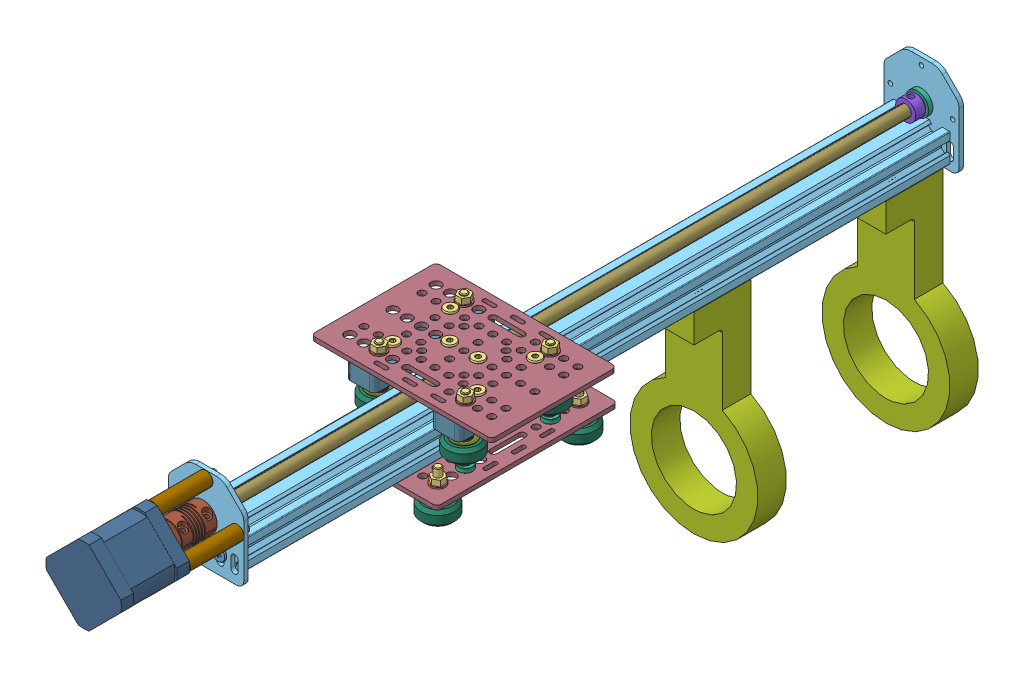
SolidWorks assembly Dispenser Actuator, configuration Default. Lengths in mm.
Overall size (127 213.42 594.1).
122 component instances, 26 part files, 152 mates.
Components (placement in the parent):
- Self Tapping Screw-1: Self Tapping Screw [Default] at (-10 5.04 578.9927) x (-0.969489 0.245134 0) z (0.245134 0.969489 0) size (9.6 20.4 9.6)
- Self Tapping Screw-3: Self Tapping Screw [Default] at (10 5.04 578.9927) x (-0.969489 0.245134 0) z (0.245134 0.969489 0) size (9.6 20.4 9.6)
- Socket Head Cap Screw M3-1: Socket Head Cap Screw M3 [M3 x 45] at (21.9203 23.47 620.9927) x (0 0 1) z (-1 0 0) size (48.09 5.5 5.5)
- Socket Head Cap Screw M3-2: Socket Head Cap Screw M3 [M3 x 45] at (0 45.3903 620.9927) x (0 0 1) z (-1 0 0) size (48.09 5.5 5.5)
- Socket Head Cap Screw M3-3: Socket Head Cap Screw M3 [M3 x 45] at (-21.9203 23.47 620.9927) x (0 0 1) z (-1 0 0) size (48.09 5.5 5.5)
- Self Tapping Screw-4: Self Tapping Screw [Default] at (10 5.04 72.9927) x (1 0 0) z (0 1 0) size (9.6 20.4 9.6)
- Self Tapping Screw-6: Self Tapping Screw [Default] at (-10 5.04 72.9927) x (1 0 0) z (0 1 0) size (9.6 20.4 9.6)
- Low Profile Screw M5-7: Low Profile Screw M5 [M5 x 15] at (-29.85 17.47 377.4168) x (0 -1 0) z (0 0 1) size (16.62 9 9)
- Low Profile Screw M5-8: Low Profile Screw M5 [M5 x 15] at (-29.85 17.47 418.0568) x (0 -1 0) z (0 0 1) size (16.62 9 9)
- Low Profile Screw M5-9: Low Profile Screw M5 [M5 x 15] at (-10 17.47 397.7368) x (0 -1 0) z (0 0 1) size (16.62 9 9)
- Low Profile Screw M5-10: Low Profile Screw M5 [M5 x 15] at (10 17.47 397.7368) x (0 -1 0) z (0 0 1) size (16.62 9 9)
- Nylon Insert Lock Nut M5-1: Nylon Insert Lock Nut M5 [Default] at (10 22.47 397.7368) x (-0.5 0 -0.866025) z (-0.866025 0 0.5) size (8 5 9.24)
- Nylon Insert Lock Nut M5-2: Nylon Insert Lock Nut M5 [Default] at (-10 22.47 397.7368) x (-0.5 0 -0.866025) z (-0.866025 0 0.5) size (8 5 9.24)
- Threaded Rod Plate Nema 17-2: Threaded Rod Plate Nema 17 [Default] at (0 23.47 578.9927) x (-1 0 0) z (0 -1 0) size (53 3 59.29)
- Threaded Rod Plate Nema 17-1: Threaded Rod Plate Nema 17 [Default] at (0 23.47 72.9927) x (1 0 0) z (0 -1 0) size (53 3 59.29)
- Ball Bearing 8 x 16 x 5-1: Ball Bearing 8 x 16 x 5 [Default] at (0 23.47 76.4927) x (0 0 1) z (-0.957169 -0.289529 0) size (5 16 16)
- Ball Bearing 8 x 16 x 5-2: Ball Bearing 8 x 16 x 5 [Default] at (0 23.47 575.4927) x (0 0 1) z (0.959032 0.283297 0) size (5 16 16)
- Shim Washer 8mm-1: Shim Washer 8mm [Default] at (0 23.47 78.9927) x (0.504051 0.863674 0) z (0.863674 -0.504051 0) size (11.8 1.15 11.8)
- Shim Washer 8mm-2: Shim Washer 8mm [Default] at (0 23.47 572.9927) x (-0.37401 -0.927425 0) z (0.927425 -0.37401 0) size (11.8 1.15 11.8)
- Lock Collar 8mm-1: Lock Collar 8mm [Default] at (0 23.47 564.8427) size (14 14 7)
- Lock Collar 8mm-2: Lock Collar 8mm [Default] at (0 23.47 80.1427) size (14 14 7)
- Aluminum Spacer 1.5in-1: Aluminum Spacer 1.5in [Default] at (-21.9203 23.47 578.9927) x (0.854977 0.518666 0) z (0 0 1) size (10 10 38.1)
- Aluminum Spacer 1.5in-2: Aluminum Spacer 1.5in [Default] at (0 45.3903 578.9927) x (0.998694 -0.051087 0) z (0 0 1) size (10 10 38.1)
- Aluminum Spacer 1.5in-3: Aluminum Spacer 1.5in [Default] at (21.9203 23.47 578.9927) x (0.68127 -0.732032 0) z (0 0 1) size (10 10 38.1)
- Nema 17 Stepper Motor-1: Nema 17 Stepper Motor [Default] at (0 23.47 617.0927) x (-0.707107 -0.707107 0) z (0 0 -1) size (42.42 42.42 72)
- Flexible Coupling 5mm x 8mm-1: Flexible Coupling 5mm x 8mm [Default] at (0 23.47 605.9927) x (0.974129 -0.225992 0) z (0 0 1) size (21.03 20 25)
- 8mm leadscrew 520mm-1: 8mm leadscrew 520mm [Default] at (0 23.47 70.9927) x (-1 0 0) z (0 0 1) size (8 8 520)
- V-Slot Gantry Plate 20-80mm-1: V-Slot Gantry Plate 20-80mm [Default] at (0 29.47 397.7368) size (127 3 88)
- Spacer Block-1: Spacer Block [Default] at (29.85 17.47 397.7368) x (0 0 1) z (0 1 0) size (86.4 20 12)
- Spacer Block-2: Spacer Block [Default] at (-29.85 17.47 397.7368) x (0 0 1) z (0 1 0) size (86.4 20 12)
- Solid V Wheel-1: Solid V Wheel [Eccentric] at (-29.85 4.97 427.7368) x (0 0 1) z (-1 0 0) size (23.9 23 23.9)
  - Solid V Wheel-1: Solid V Wheel [Default] x (0 -1 0) z (0 0 1) size (10.2 23.9 23.9)
  - Ball Bearing 5 x 16 x 5-1: Ball Bearing 5 x 16 x 5 [Default] at (0 -3 0) x (0 -1 0) z (0.990411 0 0.138155) size (5 16 16)
  - Ball Bearing 5 x 16 x 5-2: Ball Bearing 5 x 16 x 5 [Default] at (0 3 0) x (0 1 0) z (-0.887666 0 -0.460488) size (5 16 16)
  - Precision Shim 10 x 5 x 1-1: Precision Shim 10 x 5 x 1 [Default] at (0 -0.5 0) x (0.977063 0 -0.212952) z (0.212952 0 0.977063) size (10 1 10)
  - Precision Shim 10 x 5 x 1-2: Precision Shim 10 x 5 x 1 [Default] at (0 5.5 0) x (0.633048 0 -0.774113) z (0.774113 0 0.633048) size (10 1 10)
  - Nylon Insert Lock Nut M5-1: Nylon Insert Lock Nut M5 [Default] at (0 -5.5 0) x (-0.212185 0 -0.97723) z (-0.97723 0 0.212185) size (8 5 9.24)
  - Aluminum Spacer 6mm-1: Aluminum Spacer 6mm [Default] at (0 12.5 0) x (-0.695188 0 0.718828) z (0 -1 0) size (10 10 6)
- Solid V Wheel-2: Solid V Wheel [Eccentric] at (-29.85 4.97 367.7368) x (0 0 -1) z (1 0 0) size (23.9 23 23.9)
  - Solid V Wheel-1: Solid V Wheel [Default] x (0 -1 0) z (0 0 1) size (10.2 23.9 23.9)
  - Ball Bearing 5 x 16 x 5-1: Ball Bearing 5 x 16 x 5 [Default] at (0 -3 0) x (0 -1 0) z (0.990411 0 0.138155) size (5 16 16)
  - Ball Bearing 5 x 16 x 5-2: Ball Bearing 5 x 16 x 5 [Default] at (0 3 0) x (0 1 0) z (-0.887666 0 -0.460488) size (5 16 16)
  - Precision Shim 10 x 5 x 1-1: Precision Shim 10 x 5 x 1 [Default] at (0 -0.5 0) x (0.977063 0 -0.212952) z (0.212952 0 0.977063) size (10 1 10)
  - Precision Shim 10 x 5 x 1-2: Precision Shim 10 x 5 x 1 [Default] at (0 5.5 0) x (0.633048 0 -0.774113) z (0.774113 0 0.633048) size (10 1 10)
  - Nylon Insert Lock Nut M5-1: Nylon Insert Lock Nut M5 [Default] at (0 -5.5 0) x (-0.212185 0 -0.97723) z (-0.97723 0 0.212185) size (8 5 9.24)
  - Aluminum Spacer 6mm-1: Aluminum Spacer 6mm [Default] at (0 12.5 0) x (-0.695188 0 0.718828) z (0 -1 0) size (10 10 6)
- Solid V Wheel-3: Solid V Wheel [Straight] at (29.85 4.97 367.7368) x (-0.314679 0 0.949198) z (-0.949198 0 -0.314679) size (23.9 23 23.9)
  - Solid V Wheel-1: Solid V Wheel [Default] x (0 -1 0) z (0 0 1) size (10.2 23.9 23.9)
  - Ball Bearing 5 x 16 x 5-1: Ball Bearing 5 x 16 x 5 [Default] at (0 -3 0) x (0 -1 0) z (0.990411 0 0.138155) size (5 16 16)
  - Ball Bearing 5 x 16 x 5-2: Ball Bearing 5 x 16 x 5 [Default] at (0 3 0) x (0 1 0) z (-0.887666 0 -0.460488) size (5 16 16)
  - Precision Shim 10 x 5 x 1-1: Precision Shim 10 x 5 x 1 [Default] at (0 -0.5 0) x (0.977063 0 -0.212952) z (0.212952 0 0.977063) size (10 1 10)
  - Precision Shim 10 x 5 x 1-2: Precision Shim 10 x 5 x 1 [Default] at (0 5.5 0) x (0.633048 0 -0.774113) z (0.774113 0 0.633048) size (10 1 10)
  - Nylon Insert Lock Nut M5-1: Nylon Insert Lock Nut M5 [Default] at (0 -5.5 0) x (-0.212185 0 -0.97723) z (-0.97723 0 0.212185) size (8 5 9.24)
  - Aluminum Spacer 6mm-1: Aluminum Spacer 6mm [Default] at (0 12.5 0) x (-0.695188 0 0.718828) z (0 -1 0) size (10 10 6)
- Solid V Wheel-4: Solid V Wheel [Straight] at (29.85 4.97 427.7368) x (0.47214 0 -0.881524) z (0.881524 0 0.47214) size (23.9 23 23.9)
  - Solid V Wheel-1: Solid V Wheel [Default] x (0 -1 0) z (0 0 1) size (10.2 23.9 23.9)
  - Ball Bearing 5 x 16 x 5-1: Ball Bearing 5 x 16 x 5 [Default] at (0 -3 0) x (0 -1 0) z (0.990411 0 0.138155) size (5 16 16)
  - Ball Bearing 5 x 16 x 5-2: Ball Bearing 5 x 16 x 5 [Default] at (0 3 0) x (0 1 0) z (-0.887666 0 -0.460488) size (5 16 16)
  - Precision Shim 10 x 5 x 1-1: Precision Shim 10 x 5 x 1 [Default] at (0 -0.5 0) x (0.977063 0 -0.212952) z (0.212952 0 0.977063) size (10 1 10)
  - Precision Shim 10 x 5 x 1-2: Precision Shim 10 x 5 x 1 [Default] at (0 5.5 0) x (0.633048 0 -0.774113) z (0.774113 0 0.633048) size (10 1 10)
  - Nylon Insert Lock Nut M5-1: Nylon Insert Lock Nut M5 [Default] at (0 -5.5 0) x (-0.212185 0 -0.97723) z (-0.97723 0 0.212185) size (8 5 9.24)
  - Aluminum Spacer 6mm-1: Aluminum Spacer 6mm [Default] at (0 12.5 0) x (-0.695188 0 0.718828) z (0 -1 0) size (10 10 6)
- 8mm Acme Nut Block-1: 8mm Acme Nut Block [Default] at (0 23.47 387.7368) x (-1 0 0) z (0 0 1) size (34 12 20)
- Dispenser Carriage-1: Dispenser Carriage [Default] at (105.8914 54.97 431.5916) x (0 0 -1) z (-1 0 0) size (129.92 31.62 91.41)
  - V-Slot Gantry Plate 20-80mm-1: V-Slot Gantry Plate 20-80mm [Default] at (34.0048 63.5 105.4214) size (127 3 88)
  - Solid V Wheel-1: Solid V Wheel [Default] at (83.8548 77.6 75.1014) x (0 -1 0) z (0.999476 0 0.032382) size (10.2 23.9 23.9)
  - Aluminum Spacer 6mm-1: Aluminum Spacer 6mm [Default] at (83.8548 72.5 75.1014) x (0 0 -1) z (0 -1 0) size (10 10 6)
  - Ball Bearing 5 x 16 x 5-2: Ball Bearing 5 x 16 x 5 [Default] at (83.8548 75 75.1014) x (0 -1 0) z (0.999476 0 0.032382) size (5 16 16)
  - Ball Bearing 5 x 16 x 5-3: Ball Bearing 5 x 16 x 5 [Default] at (83.8548 80.2 75.1014) x (0 -1 0) z (0 0 1) size (5 16 16)
  - Low Profile Screw M5-6: Low Profile Screw M5 [M5 x 30] at (83.8548 52.7 75.1014) x (0 -1 0) z (0 0 1) size (31.62 9 9)
  - STDWasher-1: STDWasher [Default] at (83.8548 62.5 75.1014) size (10 1 10)
  - STDNut-1: STDNut [Default] at (83.8548 58.5 75.1014) size (9.24 4 8)
  - Solid V Wheel-2: Solid V Wheel [Default] at (83.8548 77.6 135.7414) x (0 -1 0) z (0.8922 0 -0.451641) size (10.2 23.9 23.9)
  - Ball Bearing 5 x 16 x 5-4: Ball Bearing 5 x 16 x 5 [Default] at (83.8548 75 135.7414) x (0 -1 0) z (0.31005 0 0.95072) size (5 16 16)
  - Ball Bearing 5 x 16 x 5-5: Ball Bearing 5 x 16 x 5 [Default] at (83.8548 80.2 135.7414) x (0 -1 0) z (0 0 1) size (5 16 16)
  - Low Profile Screw M5-7: Low Profile Screw M5 [M5 x 30] at (83.8548 52.7 135.7414) x (0 -1 0) z (0 0 1) size (31.62 9 9)
  - STDNut-2: STDNut [Default] at (83.8548 62.5 135.7414) x (0.171747 0 0.985141) z (0.985141 0 -0.171747) size (9.24 4 8)
  - STDWasher-2: STDWasher [Default] at (83.8548 63.5 135.7414) x (-0.642484 0 -0.766299) z (-0.766299 0 0.642484) size (10 1 10)
  - Aluminum Spacer 6mm-2: Aluminum Spacer 6mm [Default] at (83.8548 72.5 135.7414) x (1 0 0) z (0 -1 0) size (10 10 6)
  - Eccentric Spacer 6mm-1: Eccentric Spacer 6mm [Default] at (-15.8452 66.5 75.1014) x (0.185827 0 -0.982583) z (0.982583 0 0.185827) size (11.55 8.5 10)
  - Solid V Wheel-3: Solid V Wheel [Default] at (-15.069 77.6 75.2482) x (0 -1 0) z (0.284229 0 0.958756) size (10.2 23.9 23.9)
  - Ball Bearing 5 x 16 x 5-6: Ball Bearing 5 x 16 x 5 [Default] at (-15.069 80.2 75.2482) x (0 -1 0) z (0 0 1) size (5 16 16)
  - Ball Bearing 5 x 16 x 5-7: Ball Bearing 5 x 16 x 5 [Default] at (-15.069 75 75.2482) x (0 -1 0) z (0 0 1) size (5 16 16)
  - Low Profile Screw M5-8: Low Profile Screw M5 [M5 x 30] at (-15.069 52.7 75.2482) x (0 -1 0) z (0 0 1) size (31.62 9 9)
  - STDNut-3: STDNut [Default] at (-15.069 58.5 75.2482) size (9.24 4 8)
  - STDWasher-3: STDWasher [Default] at (-15.069 62.5 75.2482) size (10 1 10)
  - Eccentric Spacer 6mm-2: Eccentric Spacer 6mm [Default] at (-15.8452 66.5 135.7414) size (11.55 8.5 10)
  - Solid V Wheel-4: Solid V Wheel [Default] at (-15.8452 77.6 136.5314) x (0 -1 0) z (0.206271 0 -0.978495) size (10.2 23.9 23.9)
  - Ball Bearing 5 x 16 x 5-8: Ball Bearing 5 x 16 x 5 [Default] at (-15.8452 75 136.5314) x (0 -1 0) z (0 0 1) size (5 16 16)
  - Ball Bearing 5 x 16 x 5-9: Ball Bearing 5 x 16 x 5 [Default] at (-15.8452 80.2 136.5314) x (0 -1 0) z (0.107497 0 0.994205) size (5 16 16)
  - Low Profile Screw M5-9: Low Profile Screw M5 [M5 x 30] at (-15.8452 52.7 136.5314) x (0 -1 0) z (0.34232 0 0.939583) size (31.62 9 9)
  - STDNut-4: STDNut [Default] at (-15.8452 58.5 136.5314) x (0.939583 0 -0.34232) z (0.34232 0 0.939583) size (9.24 4 8)
  - STDWasher-4: STDWasher [Default] at (-15.8452 62.5 136.5314) x (0.939583 0 -0.34232) z (0.34232 0 0.939583) size (10 1 10)
- V-Slot 20x40x500 Linear Rail-1: V-Slot 20x40x500 Linear Rail [Default] at (0 5.04 75.9927) x (0 -1 0) z (0 0 1) size (20 40 500)
- Low Profile Screw M5-11: Low Profile Screw M5 [M5 x 15] at (29.85 17.47 377.4168) x (0 -1 0) z (0 0 1) size (16.62 9 9)
- Low Profile Screw M5-12: Low Profile Screw M5 [M5 x 15] at (29.85 17.47 418.0568) x (0 -1 0) z (0 0 1) size (16.62 9 9)
- Low Profile Screw M5-15: Low Profile Screw M5 [M5 x 50] at (-29.85 38.47 367.7368) x (0 1 0) z (0 0 1) size (51.62 9 9)
- STDNut-1: STDNut [Default] at (-29.85 33.47 367.7368) size (9.24 4 8)
- STDWasher-1: STDWasher [Default] at (-29.85 32.47 367.7368) size (10 1 10)
- Low Profile Screw M5-16: Low Profile Screw M5 [M5 x 50] at (-29.85 38.47 427.4368) x (0 1 0) z (0 0 1) size (51.62 9 9)
- STDNut-2: STDNut [Default] at (-29.85 33.47 427.4368) size (9.24 4 8)
- STDWasher-2: STDWasher [Default] at (-29.85 32.47 427.4368) size (10 1 10)
- Low Profile Screw M5-17: Low Profile Screw M5 [M5 x 50] at (30.79 38.47 367.7368) x (0 1 0) z (0 0 1) size (51.62 9 9)
- Low Profile Screw M5-18: Low Profile Screw M5 [M5 x 50] at (30.79 38.47 427.4368) x (0 1 0) z (0 0 1) size (51.62 9 9)
- STDNut-3: STDNut [Default] at (30.79 33.47 427.4368) size (9.24 4 8)
- STDWasher-3: STDWasher [Default] at (30.79 32.47 427.4368) size (10 1 10)
- STDNut-4: STDNut [Default] at (30.79 33.47 367.7368) size (9.24 4 8)
- STDWasher-4: STDWasher [Default] at (30.79 32.47 367.7368) size (10 1 10)
- Aluminum Spacer 3mm-1: Aluminum Spacer 3mm [Default] at (-29.85 -8.53 427.4368) x (1 0 0) z (0 1 0) size (10 10 3)
- Aluminum Spacer 3mm-2: Aluminum Spacer 3mm [Default] at (-29.85 -8.53 367.7368) x (1 0 0) z (0 1 0) size (10 10 3)
- Aluminum Spacer 3mm-3: Aluminum Spacer 3mm [Default] at (30.79 -8.53 427.4368) x (1 0 0) z (0 1 0) size (10 10 3)
- Aluminum Spacer 3mm-4: Aluminum Spacer 3mm [Default] at (30.79 -8.53 367.7368) x (1 0 0) z (0 1 0) size (10 10 3)
- CupRing-1: CupRing [Default] at (0 -114.96 80.9927) x (1 0 0) z (0 -1 0) size (90 40 155)
- CupRing-2: CupRing [Default] at (0 -114.96 215.9927) x (1 0 0) z (0 -1 0) size (90 40 155)
- Low Profile Screw M5-19: Low Profile Screw M5 [M5 x 25] at (-10 0.04 246.9927) x (0 1 0) z (0 0 1) size (26.62 9 9)
- Low Profile Screw M5-20: Low Profile Screw M5 [M5 x 25] at (10 0.04 246.9927) x (0 1 0) z (0 0 1) size (26.62 9 9)
- Low Profile Screw M5-21: Low Profile Screw M5 [M5 x 25] at (-10 0.04 111.9927) x (0 1 0) z (0 0 1) size (26.62 9 9)
- Low Profile Screw M5-22: Low Profile Screw M5 [M5 x 25] at (10 0.04 111.9927) x (0 1 0) z (0 0 1) size (26.62 9 9)
- Tee Nut-1: Tee Nut [Default] at (-10 1.14 246.9927) x (0 0 1) z (0 -1 0) size (15 10 3)
- Tee Nut-2: Tee Nut [Default] at (10 1.14 246.9927) x (0 0 -1) z (0 -1 0) size (15 10 3)
- Tee Nut-3: Tee Nut [Default] at (-10 1.14 111.9927) x (0 0 -1) z (0 -1 0) size (15 10 3)
- Tee Nut-4: Tee Nut [Default] at (10 1.14 111.9927) x (0 0 -1) z (0 -1 0) size (15 10 3)
Mates (geometry in assembly coordinates):
- Concentric1: concentric anti-aligned: cylinder of Threaded Rod Plate Nema 17-1 through (0 23.47 75.9927) axis (0 0 -1) radius 5.5; cylinder of Ball Bearing 8 x 16 x 5-1 through (0 23.47 76.4927) axis (0 0 1) radius 8
- Coincident10: coincident anti-aligned: plane of Threaded Rod Plate Nema 17-1 through (0 23.47 73.9927) normal (0 0 1); plane of Ball Bearing 8 x 16 x 5-1 through (-2.0846 30.3617 73.9927) normal (0 0 -1)
- Concentric2: concentric anti-aligned: cylinder of Threaded Rod Plate Nema 17-2 through (0 23.47 577.9927) axis (0 0 -1) radius 8.025; cylinder of Ball Bearing 8 x 16 x 5-2 through (0 23.47 575.4927) axis (0 0 1) radius 8
- Coincident11: coincident anti-aligned: plane of Threaded Rod Plate Nema 17-2 through (0 23.47 577.9927) normal (0 0 -1); plane of Ball Bearing 8 x 16 x 5-2 through (2.0397 16.565 577.9927) normal (0 0 1)
- Concentric3: concentric anti-aligned: cylinder of Ball Bearing 8 x 16 x 5-1 through (0 23.47 76.4927) axis (0 0 1) radius 5.1; cylinder of Shim Washer 8mm-1 through (0 23.47 80.1427) axis (0 0 -1) radius 4.25
- Coincident12: coincident anti-aligned: plane of Ball Bearing 8 x 16 x 5-1 through (-1.1581 27.2987 78.9927) normal (0 0 1); plane of Shim Washer 8mm-1 through (0 23.47 78.9927) normal (0 0 -1)
- Concentric4: concentric aligned: cylinder of Ball Bearing 8 x 16 x 5-2 through (0 23.47 575.4927) axis (0 0 1) radius 4; cylinder of Shim Washer 8mm-2 through (0 23.47 571.8427) axis (0 0 1) radius 4.25
- Coincident13: coincident anti-aligned: plane of Ball Bearing 8 x 16 x 5-2 through (1.1332 19.6339 572.9927) normal (0 0 -1); plane of Shim Washer 8mm-2 through (0 23.47 572.9927) normal (0 0 1)
- Concentric5: concentric anti-aligned: cylinder of Shim Washer 8mm-2 through (0 23.47 571.8427) axis (0 0 1) radius 5.9; cylinder of Lock Collar 8mm-1 through (0 23.47 571.8427) axis (0 0 -1) radius 4
- Coincident14: coincident anti-aligned: plane of Shim Washer 8mm-2 through (0 23.47 571.8427) normal (0 0 -1); plane of Lock Collar 8mm-1 through (0 23.47 571.8427) normal (0 0 1)
- Concentric6: concentric aligned: cylinder of Shim Washer 8mm-1 through (0 23.47 80.1427) axis (0 0 -1) radius 4.25; cylinder of Lock Collar 8mm-2 through (0 23.47 87.1427) axis (0 0 -1) radius 4
- Coincident15: coincident anti-aligned: plane of Shim Washer 8mm-1 through (0 23.47 80.1427) normal (0 0 1); plane of Lock Collar 8mm-2 through (0 23.47 80.1427) normal (0 0 -1)
- Parallel1: parallel aligned: plane of Lock Collar 8mm-1 through (0 23.47 564.8427) normal (0 1 0); plane of assembly through (0 0 0) normal (0 1 0)
- Parallel2: parallel aligned: plane of Lock Collar 8mm-2 through (0 23.47 80.1427) normal (0 1 0); plane of assembly through (0 0 0) normal (0 1 0)
- Coincident18: coincident anti-aligned: plane of Threaded Rod Plate Nema 17-2 through (21.5 -3.96 578.9927) normal (0 0 1); plane of Self Tapping Screw-1 through (-7.649 4.4456 578.9927) normal (0 0 -1)
- Coincident201: coincident anti-aligned: plane of Threaded Rod Plate Nema 17-2 through (21.5 -3.96 578.9927) normal (0 0 1); plane of Self Tapping Screw-3 through (12.351 4.4456 578.9927) normal (0 0 -1)
- Concentric10: concentric anti-aligned: cylinder of Threaded Rod Plate Nema 17-2 through (-21.9203 23.47 575.9927) axis (0 0 1) radius 1.6; cone of Aluminum Spacer 1.5in-1 through (-21.9203 23.47 579.1927) axis (0 0 -1)
- Coincident21: coincident anti-aligned: plane of Threaded Rod Plate Nema 17-2 through (21.5 -3.96 578.9927) normal (0 0 1); plane of Aluminum Spacer 1.5in-1 through (-21.9203 23.47 578.9927) normal (0 0 -1)
- Concentric11: concentric anti-aligned: cylinder of Threaded Rod Plate Nema 17-2 through (0 45.3903 575.9927) axis (0 0 1) radius 1.6; cone of Aluminum Spacer 1.5in-2 through (0 45.3903 579.1927) axis (0 0 -1)
- Coincident22: coincident anti-aligned: plane of Threaded Rod Plate Nema 17-2 through (21.5 -3.96 578.9927) normal (0 0 1); plane of Aluminum Spacer 1.5in-2 through (0 45.3903 578.9927) normal (0 0 -1)
- Concentric12: concentric anti-aligned: cylinder of Threaded Rod Plate Nema 17-2 through (21.9203 23.47 575.9927) axis (0 0 1) radius 1.6; cone of Aluminum Spacer 1.5in-3 through (21.9203 23.47 579.1927) axis (0 0 -1)
- Coincident23: coincident anti-aligned: plane of Threaded Rod Plate Nema 17-2 through (21.5 -3.96 578.9927) normal (0 0 1); plane of Aluminum Spacer 1.5in-3 through (21.9203 23.47 578.9927) normal (0 0 -1)
- Concentric13: concentric aligned: cone of Aluminum Spacer 1.5in-2 through (0 45.3903 616.8927) axis (0 0 -1); cylinder of Nema 17 Stepper Motor-1 through (0 45.3903 617.0927) axis (0 0 -1) radius 1.5
- Coincident24: coincident anti-aligned: plane of Aluminum Spacer 1.5in-2 through (0 45.3903 617.0927) normal (0 0 1); plane of Nema 17 Stepper Motor-1 through (0 23.47 617.0927) normal (0 0 -1)
- Concentric15: concentric aligned: cylinder of Aluminum Spacer 1.5in-1 through (-21.9203 23.47 617.0927) axis (0 0 -1) radius 2.55; cylinder of Nema 17 Stepper Motor-1 through (-21.9203 23.47 617.0927) axis (0 0 -1) radius 1.5
- Concentric161: concentric anti-aligned: cylinder of Threaded Rod Plate Nema 17-2 through (21.9203 23.47 575.9927) axis (0 0 1) radius 1.6; cylinder of Socket Head Cap Screw M3-1 through (21.9203 23.47 575.9927) axis (0 0 -1) radius 2.75
- Coincident251: coincident anti-aligned: plane of Threaded Rod Plate Nema 17-2 through (21.5 -3.96 575.9927) normal (0 0 -1); plane of Socket Head Cap Screw M3-1 through (21.9203 26.22 575.9927) normal (0 0 1)
- Concentric171: concentric anti-aligned: cylinder of Threaded Rod Plate Nema 17-2 through (0 45.3903 575.9927) axis (0 0 1) radius 1.6; cylinder of Socket Head Cap Screw M3-2 through (0 45.3903 575.9927) axis (0 0 -1) radius 2.75
- Coincident261: coincident anti-aligned: plane of Threaded Rod Plate Nema 17-2 through (21.5 -3.96 575.9927) normal (0 0 -1); plane of Socket Head Cap Screw M3-2 through (0 48.1403 575.9927) normal (0 0 1)
- Concentric181: concentric anti-aligned: cylinder of Threaded Rod Plate Nema 17-2 through (-21.9203 23.47 575.9927) axis (0 0 1) radius 1.6; cylinder of Socket Head Cap Screw M3-3 through (-21.9203 23.47 575.9927) axis (0 0 -1) radius 2.75
- Coincident271: coincident anti-aligned: plane of Threaded Rod Plate Nema 17-2 through (21.5 -3.96 575.9927) normal (0 0 -1); plane of Socket Head Cap Screw M3-3 through (-21.9203 26.22 575.9927) normal (0 0 1)
- Coincident281: coincident anti-aligned: plane of Threaded Rod Plate Nema 17-1 through (-21.5 -3.96 72.9927) normal (0 0 -1); plane of Self Tapping Screw-4 through (7.575 5.04 72.9927) normal (0 0 1)
- Coincident301: coincident anti-aligned: plane of Threaded Rod Plate Nema 17-1 through (-21.5 -3.96 72.9927) normal (0 0 -1); plane of Self Tapping Screw-6 through (-12.425 5.04 72.9927) normal (0 0 1)
- Concentric22: concentric aligned: cylinder of Nema 17 Stepper Motor-1 through (0 23.47 593.0927) axis (0 0 1) radius 2.5; cylinder of Flexible Coupling 5mm x 8mm-1 through (0 23.47 580.9927) axis (0 0 1) radius 2.5
- Concentric23: concentric anti-aligned: cylinder of Ball Bearing 8 x 16 x 5-2 through (0 23.47 575.4927) axis (0 0 1) radius 4; cylinder of 8mm leadscrew 520mm-1 through (0 23.47 590.9927) axis (0 0 -1) radius 4
- Distance5: distance = 2 mm aligned: plane of Threaded Rod Plate Nema 17-1 through (-21.5 -3.96 72.9927) normal (0 0 -1); plane of 8mm leadscrew 520mm-1 through (0 23.47 70.9927) normal (0 0 -1)
- Distance1: distance = 2 mm anti-aligned: plane of Flexible Coupling 5mm x 8mm-1 through (0 23.47 580.9927) normal (0 0 -1); plane of Threaded Rod Plate Nema 17-2 through (21.5 -3.96 578.9927) normal (0 0 1)
- Coincident33: coincident anti-aligned: plane of V-Slot Gantry Plate 20-80mm-1 through (-60.5 29.47 438.7368) normal (0 -1 0); plane of Spacer Block-1 through (36.49 29.47 437.5768) normal (0 1 0)
- Parallel5: parallel aligned: plane of V-Slot Gantry Plate 20-80mm-1 through (63.5 32.47 438.7368) normal (1 0 0); plane of Spacer Block-1 through (39.85 29.47 437.5768) normal (1 0 0)
- Concentric26: concentric anti-aligned: cylinder of Spacer Block-1 through (29.85 17.47 397.7368) axis (0 1 0) radius 3.6; cylinder of V-Slot Gantry Plate 20-80mm-1 through (29.85 32.47 397.7368) axis (0 -1 0) radius 2.55
- Coincident35: coincident anti-aligned: plane of V-Slot Gantry Plate 20-80mm-1 through (-60.5 29.47 438.7368) normal (0 -1 0); plane of Spacer Block-2 through (-23.21 29.47 437.5768) normal (0 1 0)
- Concentric27: concentric anti-aligned: cylinder of Spacer Block-2 through (-29.85 17.47 397.7368) axis (0 1 0) radius 3.6; cylinder of V-Slot Gantry Plate 20-80mm-1 through (-29.85 32.47 397.7368) axis (0 -1 0) radius 3.55
- Parallel6: parallel aligned: plane of V-Slot Gantry Plate 20-80mm-1 through (-63.5 32.47 438.7368) normal (-1 0 0); plane of Spacer Block-2 through (-39.85 29.47 437.5768) normal (-1 0 0)
- Coincident37: coincident anti-aligned: plane of Spacer Block-1 through (36.49 17.47 437.5768) normal (0 -1 0); plane of Solid V Wheel-4/Aluminum Spacer 6mm-1 through (29.85 17.47 427.7368) normal (0 1 0)
- Concentric28: concentric aligned: cylinder of Spacer Block-1 through (29.85 17.47 427.7368) axis (0 1 0) radius 3.6; cylinder of Solid V Wheel-4/Aluminum Spacer 6mm-1 through (29.85 11.47 427.7368) axis (0 1 0) radius 2.55
- Coincident38: coincident anti-aligned: plane of Spacer Block-1 through (36.49 17.47 437.5768) normal (0 -1 0); plane of Solid V Wheel-3/Aluminum Spacer 6mm-1 through (29.85 17.47 367.7368) normal (0 1 0)
- Concentric29: concentric aligned: cylinder of Spacer Block-1 through (29.85 17.47 367.7368) axis (0 1 0) radius 3.6; cylinder of Solid V Wheel-3/Aluminum Spacer 6mm-1 through (29.85 11.47 367.7368) axis (0 1 0) radius 2.55
- Coincident39: coincident anti-aligned: plane of Spacer Block-2 through (-33.21 12.5 326.1111) normal (0 -1 0); plane of ? through (-39.85 12.5 316.2711) normal (0 1 0)
- Concentric30: concentric anti-aligned: cylinder of Spacer Block-2 through (-39.85 12.5 316.2711) axis (0 1 0) radius 3.6; cylinder of ? through (-39.85 15 316.2711) axis (0 -1 0) radius 3.555
- Coincident40: coincident anti-aligned: plane of Spacer Block-2 through (-33.21 12.5 326.1111) normal (0 -1 0); plane of ? through (-39.85 12.5 256.2711) normal (0 1 0)
- Parallel7: parallel aligned: plane of Spacer Block-2 through (-46.49 24.5 329.4711) normal (0 0 1); plane of ? through (-36.9632 6.5 321.2711) normal (0 0 1)
- Parallel8: parallel aligned: plane of Spacer Block-2 through (-46.49 24.5 243.0711) normal (0 0 -1); plane of ? through (-42.7368 6.5 251.2711) normal (0 0 -1)
- Coincident511: coincident anti-aligned: plane of V-Slot Gantry Plate 20-80mm-1 through (-60.5 32.47 438.7368) normal (0 1 0); plane of Low Profile Screw M5-7 through (-25.6886 32.47 377.4168) normal (0 -1 0)
- Concentric411: concentric aligned: cylinder of Low Profile Screw M5-8 through (-29.85 32.47 418.0568) axis (0 -1 0) radius 2.5; cylinder of V-Slot Gantry Plate 20-80mm-1 through (-29.85 32.47 418.0568) axis (0 -1 0) radius 2.55
- Coincident521: coincident anti-aligned: plane of V-Slot Gantry Plate 20-80mm-1 through (-60.5 32.47 438.7368) normal (0 1 0); plane of Low Profile Screw M5-8 through (-25.6886 32.47 418.0568) normal (0 -1 0)
- Concentric421: concentric aligned: cylinder of V-Slot Gantry Plate 20-80mm-1 through (-10 32.47 397.7368) axis (0 -1 0) radius 2.55; cylinder of Low Profile Screw M5-9 through (-10 32.47 397.7368) axis (0 -1 0) radius 2.5
- Coincident531: coincident anti-aligned: plane of V-Slot Gantry Plate 20-80mm-1 through (-60.5 32.47 438.7368) normal (0 1 0); plane of Low Profile Screw M5-9 through (-5.8386 32.47 397.7368) normal (0 -1 0)
- Concentric431: concentric aligned: cylinder of V-Slot Gantry Plate 20-80mm-1 through (10 32.47 397.7368) axis (0 -1 0) radius 2.55; cylinder of Low Profile Screw M5-10 through (10 32.47 397.7368) axis (0 -1 0) radius 2.5
- Coincident541: coincident anti-aligned: plane of V-Slot Gantry Plate 20-80mm-1 through (-60.5 32.47 438.7368) normal (0 1 0); plane of Low Profile Screw M5-10 through (14.1614 32.47 397.7368) normal (0 -1 0)
- Coincident55: coincident anti-aligned: plane of V-Slot Gantry Plate 20-80mm-1 through (-60.5 29.47 438.7368) normal (0 -1 0); plane of 8mm Acme Nut Block-1 through (-17 29.47 407.7368) normal (0 1 0)
- Concentric44: concentric aligned: cylinder of V-Slot Gantry Plate 20-80mm-1 through (-10 32.47 397.7368) axis (0 -1 0) radius 2.55; cylinder of 8mm Acme Nut Block-1 through (-10 29.47 397.7368) axis (0 -1 0) radius 2.55
- Concentric45: concentric aligned: cylinder of V-Slot Gantry Plate 20-80mm-1 through (10 32.47 397.7368) axis (0 -1 0) radius 2.55; cylinder of 8mm Acme Nut Block-1 through (10 29.47 397.7368) axis (0 -1 0) radius 2.55
- Concentric46: concentric anti-aligned: cylinder of 8mm Acme Nut Block-1 through (10 29.47 397.7368) axis (0 -1 0) radius 2.55; cylinder of Nylon Insert Lock Nut M5-1 through (10 22.47 397.7368) axis (0 1 0) radius 2.5
- Coincident56: coincident anti-aligned: plane of 8mm Acme Nut Block-1 through (0 22.47 387.7368) normal (0 -1 0); plane of Nylon Insert Lock Nut M5-1 through (11.25 22.47 399.9019) normal (0 1 0)
- Concentric47: concentric anti-aligned: cylinder of 8mm Acme Nut Block-1 through (-10 29.47 397.7368) axis (0 -1 0) radius 2.55; cylinder of Nylon Insert Lock Nut M5-2 through (-10 22.47 397.7368) axis (0 1 0) radius 2.5
- Coincident57: coincident anti-aligned: plane of 8mm Acme Nut Block-1 through (0 22.47 387.7368) normal (0 -1 0); plane of Nylon Insert Lock Nut M5-2 through (-8.75 22.47 399.9019) normal (0 1 0)
- Parallel11: parallel anti-aligned: plane of 8mm Acme Nut Block-1 through (-6 22.47 400.0462) normal (-1 0 0); plane of Nylon Insert Lock Nut M5-2 through (-6 17.47 400.0462) normal (1 0 0)
- Parallel12: parallel anti-aligned: plane of 8mm Acme Nut Block-1 through (14 22.47 395.4274) normal (-1 0 0); plane of Nylon Insert Lock Nut M5-1 through (14 17.47 400.0462) normal (1 0 0)
- Coincident542: coincident anti-aligned: plane of Threaded Rod Plate Nema 17-1 through (-21.5 -3.96 75.9927) normal (0 0 1); plane of V-Slot 20x40x500 Linear Rail-1 through (0 5.04 75.9927) normal (0 0 -1)
- Coincident543: coincident anti-aligned: plane of Threaded Rod Plate Nema 17-2 through (21.5 -3.96 575.9927) normal (0 0 -1); plane of V-Slot 20x40x500 Linear Rail-1 through (0 5.04 575.9927) normal (0 0 1)
- Coincident544: coincident aligned: plane of V-Slot 20x40x500 Linear Rail-1; plane of assembly through (0 0 0) normal (1 0 0)
- Distance6: distance = 4 mm aligned: plane of V-Slot 20x40x500 Linear Rail-1 through (0 -4.96 575.9927) normal (0 -1 0); plane of Threaded Rod Plate Nema 17-1 through (21.5 -8.96 75.9927) normal (0 -1 0)
- Concentric432: concentric aligned: cylinder of Self Tapping Screw-6 through (-10 5.04 91.9927) axis (0 0 -1) radius 2.425; cylinder of V-Slot 20x40x500 Linear Rail-1 through (-10 5.04 575.9927) axis (0 0 -1) radius 2.1
- Concentric433: concentric aligned: cylinder of Self Tapping Screw-4 through (10 5.04 91.9927) axis (0 0 -1) radius 2.425; cylinder of V-Slot 20x40x500 Linear Rail-1 through (10 5.04 575.9927) axis (0 0 -1) radius 2.1
- Concentric434: concentric anti-aligned: cylinder of Self Tapping Screw-1 through (-10 5.04 559.9927) axis (0 0 1) radius 2.425; cylinder of V-Slot 20x40x500 Linear Rail-1 through (-10 5.04 575.9927) axis (0 0 -1) radius 2.1
- Concentric435: concentric anti-aligned: cylinder of Self Tapping Screw-3 through (10 5.04 559.9927) axis (0 0 1) radius 1.95; cylinder of V-Slot 20x40x500 Linear Rail-1 through (10 5.04 575.9927) axis (0 0 -1) radius 2.1
- Distance7: distance = 4 mm aligned: plane of V-Slot 20x40x500 Linear Rail-1 through (0 -4.96 575.9927) normal (0 -1 0); plane of Threaded Rod Plate Nema 17-2 through (-21.5 -8.96 575.9927) normal (0 -1 0)
- Coincident547: coincident anti-aligned: plane of 8mm leadscrew 520mm-1; plane of V-Slot 20x40x500 Linear Rail-1
- Parallel15: parallel anti-aligned: plane of V-Slot Gantry Plate 20-80mm-1 through (-60.5 29.47 438.7368) normal (0 -1 0); plane of V-Slot 20x40x500 Linear Rail-1 through (0 15.04 575.9927) normal (0 1 0)
- Concentric437: concentric anti-aligned: cylinder of 8mm leadscrew 520mm-1 through (0 23.47 590.9927) axis (0 0 -1) radius 4; cylinder of 8mm Acme Nut Block-1 through (0 23.47 387.7368) axis (0 0 1) radius 4
- Concentric438: concentric aligned: cylinder of Low Profile Screw M5-7 through (-29.85 32.47 377.4168) axis (0 -1 0) radius 2.5; cylinder of V-Slot Gantry Plate 20-80mm-1 through (-29.85 32.47 377.4168) axis (0 -1 0) radius 2.55
- Concentric439: concentric aligned: cylinder of V-Slot Gantry Plate 20-80mm-1 through (29.85 32.47 377.4168) axis (0 -1 0) radius 2.55; cylinder of Low Profile Screw M5-11 through (29.85 32.47 377.4168) axis (0 -1 0) radius 2.5
- Coincident550: coincident anti-aligned: plane of V-Slot Gantry Plate 20-80mm-1 through (-60.5 32.47 438.7368) normal (0 1 0); plane of Low Profile Screw M5-11 through (34.0114 32.47 377.4168) normal (0 -1 0)
- Coincident551: coincident anti-aligned: plane of V-Slot Gantry Plate 20-80mm-1 through (-60.5 32.47 438.7368) normal (0 1 0); plane of Low Profile Screw M5-12 through (34.0114 32.47 418.0568) normal (0 -1 0)
- Concentric440: concentric aligned: cylinder of V-Slot Gantry Plate 20-80mm-1 through (29.85 32.47 418.0568) axis (0 -1 0) radius 2.55; cylinder of Low Profile Screw M5-12 through (29.85 32.47 418.0568) axis (0 -1 0) radius 2.5
- Concentric441: concentric aligned: cylinder of Spacer Block-2 through (-29.85 17.47 367.7368) axis (0 1 0) radius 3.6; cylinder of Solid V Wheel-2/Aluminum Spacer 6mm-1 through (-29.85 11.47 367.7368) axis (0 1 0) radius 2.55
- Coincident552: coincident anti-aligned: plane of Spacer Block-2 through (-23.21 17.47 437.5768) normal (0 -1 0); plane of Solid V Wheel-2/Aluminum Spacer 6mm-1 through (-29.85 17.47 367.7368) normal (0 1 0)
- Concentric442: concentric aligned: cylinder of Spacer Block-2 through (-29.85 17.47 427.7368) axis (0 1 0) radius 3.6; cylinder of Solid V Wheel-1/Aluminum Spacer 6mm-1 through (-29.85 11.47 427.7368) axis (0 1 0) radius 2.55
- Coincident553: coincident anti-aligned: plane of Spacer Block-2 through (-23.21 17.47 437.5768) normal (0 -1 0); plane of Solid V Wheel-1/Aluminum Spacer 6mm-1 through (-29.85 17.47 427.7368) normal (0 1 0)
- Concentric444: concentric aligned: cylinder of Dispenser Carriage-1/V-Slot Gantry Plate 20-80mm-1 through (-29.85 -11.53 367.7368) axis (0 1 0) radius 2.55; cylinder of Low Profile Screw M5-15 through (-29.85 -11.53 367.7368) axis (0 1 0) radius 2.5
- Coincident555: coincident anti-aligned: plane of Dispenser Carriage-1/V-Slot Gantry Plate 20-80mm-1 through (-40.53 -11.53 458.0868) normal (0 -1 0); plane of Low Profile Screw M5-15 through (-34.0114 -11.53 367.7368) normal (0 1 0)
- Coincident556: coincident anti-aligned: plane of V-Slot Gantry Plate 20-80mm-1 through (-60.5 32.47 438.7368) normal (0 1 0); plane of STDWasher-1 through (-29.85 32.47 367.7368) normal (0 -1 0)
- Concentric446: concentric aligned: cylinder of Spacer Block-2 through (-29.85 17.47 367.7368) axis (0 1 0) radius 3.6; cylinder of Low Profile Screw M5-15 through (-29.85 -11.53 367.7368) axis (0 1 0) radius 2.5
- Concentric447: concentric anti-aligned: cylinder of Low Profile Screw M5-15 through (-29.85 -11.53 367.7368) axis (0 1 0) radius 2.5; cylinder of STDWasher-1 through (-29.85 33.47 367.7368) axis (0 -1 0) radius 2.5
- Concentric448: concentric anti-aligned: cylinder of Low Profile Screw M5-15 through (-29.85 -11.53 367.7368) axis (0 1 0) radius 2.5; cylinder of STDNut-1 through (-29.85 37.47 367.7368) axis (0 -1 0) radius 2.5
- Coincident558: coincident anti-aligned: plane of STDNut-1 through (-29.85 33.47 367.7368) normal (0 -1 0); plane of STDWasher-1 through (-29.85 33.47 367.7368) normal (0 1 0)
- Concentric449: concentric aligned: cylinder of Dispenser Carriage-1/V-Slot Gantry Plate 20-80mm-1 through (-29.85 -11.53 427.4368) axis (0 1 0) radius 3.55; cylinder of Low Profile Screw M5-16 through (-29.85 -11.53 427.4368) axis (0 1 0) radius 2.5
- Coincident559: coincident anti-aligned: plane of Dispenser Carriage-1/V-Slot Gantry Plate 20-80mm-1 through (-40.53 -11.53 458.0868) normal (0 -1 0); plane of Low Profile Screw M5-16 through (-34.0114 -11.53 427.4368) normal (0 1 0)
- Concentric450: concentric anti-aligned: cylinder of Low Profile Screw M5-16 through (-29.85 -11.53 427.4368) axis (0 1 0) radius 2.5; cylinder of STDWasher-2 through (-29.85 33.47 427.4368) axis (0 -1 0) radius 2.5
- Coincident560: coincident anti-aligned: plane of V-Slot Gantry Plate 20-80mm-1 through (-60.5 32.47 438.7368) normal (0 1 0); plane of STDWasher-2 through (-29.85 32.47 427.4368) normal (0 -1 0)
- Coincident561: coincident anti-aligned: plane of STDNut-2 through (-29.85 33.47 427.4368) normal (0 -1 0); plane of STDWasher-2 through (-29.85 33.47 427.4368) normal (0 1 0)
- Concentric451: concentric anti-aligned: cylinder of Low Profile Screw M5-16 through (-29.85 -11.53 427.4368) axis (0 1 0) radius 2.5; cylinder of STDNut-2 through (-29.85 37.47 427.4368) axis (0 -1 0) radius 2.5
- Concentric452: concentric aligned: cylinder of Dispenser Carriage-1/V-Slot Gantry Plate 20-80mm-1 through (30.79 -11.53 427.4368) axis (0 1 0) radius 3.55; cylinder of Low Profile Screw M5-18 through (30.79 -11.53 427.4368) axis (0 1 0) radius 2.5
- Coincident562: coincident anti-aligned: plane of Dispenser Carriage-1/V-Slot Gantry Plate 20-80mm-1 through (-40.53 -11.53 458.0868) normal (0 -1 0); plane of Low Profile Screw M5-18 through (26.6286 -11.53 427.4368) normal (0 1 0)
- Concentric453: concentric aligned: cylinder of Dispenser Carriage-1/V-Slot Gantry Plate 20-80mm-1 through (30.79 -11.53 367.7368) axis (0 1 0) radius 2.55; cylinder of Low Profile Screw M5-17 through (30.79 -11.53 367.7368) axis (0 1 0) radius 2.5
- Coincident563: coincident anti-aligned: plane of Dispenser Carriage-1/V-Slot Gantry Plate 20-80mm-1 through (-40.53 -11.53 458.0868) normal (0 -1 0); plane of Low Profile Screw M5-17 through (26.6286 -11.53 367.7368) normal (0 1 0)
- Coincident564: coincident anti-aligned: plane of V-Slot Gantry Plate 20-80mm-1 through (-60.5 32.47 438.7368) normal (0 1 0); plane of STDWasher-3 through (30.79 32.47 427.4368) normal (0 -1 0)
- Concentric454: concentric anti-aligned: cylinder of Low Profile Screw M5-18 through (30.79 -11.53 427.4368) axis (0 1 0) radius 2.5; cylinder of STDWasher-3 through (30.79 33.47 427.4368) axis (0 -1 0) radius 2.5
- Concentric455: concentric anti-aligned: cylinder of Low Profile Screw M5-18 through (30.79 -11.53 427.4368) axis (0 1 0) radius 2.5; cylinder of STDNut-3 through (30.79 37.47 427.4368) axis (0 -1 0) radius 2.5
- Coincident565: coincident anti-aligned: plane of STDNut-3 through (30.79 33.47 427.4368) normal (0 -1 0); plane of STDWasher-3 through (30.79 33.47 427.4368) normal (0 1 0)
- Coincident566: coincident anti-aligned: plane of V-Slot Gantry Plate 20-80mm-1 through (-60.5 32.47 438.7368) normal (0 1 0); plane of STDWasher-4 through (30.79 32.47 367.7368) normal (0 -1 0)
- Concentric456: concentric anti-aligned: cylinder of Low Profile Screw M5-17 through (30.79 -11.53 367.7368) axis (0 1 0) radius 2.5; cylinder of STDWasher-4 through (30.79 33.47 367.7368) axis (0 -1 0) radius 2.5
- Coincident567: coincident anti-aligned: plane of STDNut-4 through (30.79 33.47 367.7368) normal (0 -1 0); plane of STDWasher-4 through (30.79 33.47 367.7368) normal (0 1 0)
- Concentric457: concentric anti-aligned: cylinder of Low Profile Screw M5-17 through (30.79 -11.53 367.7368) axis (0 1 0) radius 2.5; cylinder of STDNut-4 through (30.79 37.47 367.7368) axis (0 -1 0) radius 2.5
- Parallel17: parallel aligned: plane of V-Slot Gantry Plate 20-80mm-1 through (-63.5 32.47 438.7368) normal (-1 0 0); plane of Dispenser Carriage-1/V-Slot Gantry Plate 20-80mm-1 through (-43.53 -11.53 337.0868) normal (-1 0 0)
- Parallel18: parallel aligned: plane of V-Slot Gantry Plate 20-80mm-1 through (60.5 32.47 441.7368) normal (0 0 1); plane of Dispenser Carriage-1/V-Slot Gantry Plate 20-80mm-1 through (-40.53 -11.53 461.0868) normal (0 0 1)
- Coincident570: coincident anti-aligned: plane of Lock Collar 8mm-2 through (0 23.47 80.1427) normal (1 0 0); plane of 8mm leadscrew 520mm-1
- Concentric461: concentric anti-aligned: cylinder of Low Profile Screw M5-16 through (-29.85 -11.53 427.4368) axis (0 1 0) radius 2.5; cylinder of Aluminum Spacer 3mm-1 through (-29.85 -5.53 427.4368) axis (0 -1 0) radius 2.55
- Coincident575: coincident anti-aligned: plane of Solid V Wheel-1/Nylon Insert Lock Nut M5-1 through (-32.9478 -5.53 428.4094) normal (0 -1 0); plane of Aluminum Spacer 3mm-1 through (-29.85 -5.53 427.4368) normal (0 1 0)
- Coincident576: coincident anti-aligned: plane of Dispenser Carriage-1/V-Slot Gantry Plate 20-80mm-1 through (-40.53 -8.53 458.0868) normal (0 1 0); plane of Aluminum Spacer 3mm-1 through (-29.85 -8.53 427.4368) normal (0 -1 0)
- Concentric462: concentric anti-aligned: cylinder of Low Profile Screw M5-15 through (-29.85 -11.53 367.7368) axis (0 1 0) radius 2.5; cylinder of Aluminum Spacer 3mm-2 through (-29.85 -5.53 367.7368) axis (0 -1 0) radius 2.55
- Coincident578: coincident anti-aligned: plane of Dispenser Carriage-1/V-Slot Gantry Plate 20-80mm-1 through (-40.53 -8.53 458.0868) normal (0 1 0); plane of Aluminum Spacer 3mm-2 through (-29.85 -8.53 367.7368) normal (0 -1 0)
- Concentric463: concentric anti-aligned: cylinder of Low Profile Screw M5-17 through (30.79 -11.53 367.7368) axis (0 1 0) radius 2.5; cylinder of Aluminum Spacer 3mm-4 through (30.79 -5.53 367.7368) axis (0 -1 0) radius 2.55
- Coincident579: coincident anti-aligned: plane of Dispenser Carriage-1/V-Slot Gantry Plate 20-80mm-1 through (-40.53 -8.53 458.0868) normal (0 1 0); plane of Aluminum Spacer 3mm-4 through (30.79 -8.53 367.7368) normal (0 -1 0)
- Concentric464: concentric anti-aligned: cylinder of Low Profile Screw M5-18 through (30.79 -11.53 427.4368) axis (0 1 0) radius 2.5; cylinder of Aluminum Spacer 3mm-3 through (30.79 -5.53 427.4368) axis (0 -1 0) radius 2.55
- Coincident580: coincident anti-aligned: plane of Dispenser Carriage-1/V-Slot Gantry Plate 20-80mm-1 through (-40.53 -8.53 458.0868) normal (0 1 0); plane of Aluminum Spacer 3mm-3 through (30.79 -8.53 427.4368) normal (0 -1 0)
- Coincident581: coincident anti-aligned: plane of V-Slot 20x40x500 Linear Rail-1 through (0 -4.96 575.9927) normal (0 -1 0); plane of CupRing-1 through (-20 -4.96 190.4354) normal (0 1 0)
- Distance8: distance = 5 mm anti-aligned: plane of Threaded Rod Plate Nema 17-1 through (-21.5 -3.96 75.9927) normal (0 0 1); plane of CupRing-1 through (0 -114.96 80.9927) normal (0 0 -1)
- Coincident583: coincident aligned: plane of V-Slot 20x40x500 Linear Rail-1; plane of CupRing-1
- Coincident584: coincident anti-aligned: plane of V-Slot 20x40x500 Linear Rail-1 through (0 -4.96 575.9927) normal (0 -1 0); plane of CupRing-2 through (-20 -4.96 325.4354) normal (0 1 0)
- Coincident585: coincident aligned: plane of V-Slot 20x40x500 Linear Rail-1; plane of CupRing-2
- Distance9: distance = 140 mm anti-aligned: plane of CupRing-2 through (0 -114.96 215.9927) normal (0 0 -1); plane of Threaded Rod Plate Nema 17-1 through (-21.5 -3.96 75.9927) normal (0 0 1)
- Concentric465: concentric anti-aligned: cylinder of CupRing-2 through (-10 -4.96 246.9927) axis (0 -1 0) radius 4; cylinder of Low Profile Screw M5-19 through (-10 -24.96 246.9927) axis (0 1 0) radius 2.5
- Coincident587: coincident anti-aligned: plane of CupRing-2 through (-20 -24.96 255.9927) normal (0 -1 0); plane of Low Profile Screw M5-19 through (-14.1614 -24.96 246.9927) normal (0 1 0)
- Concentric466: concentric anti-aligned: cylinder of CupRing-2 through (10 -4.96 246.9927) axis (0 -1 0) radius 4; cylinder of Low Profile Screw M5-20 through (10 -24.96 246.9927) axis (0 1 0) radius 2.5
- Coincident588: coincident anti-aligned: plane of CupRing-2 through (-20 -24.96 255.9927) normal (0 -1 0); plane of Low Profile Screw M5-20 through (5.8386 -24.96 246.9927) normal (0 1 0)
- Concentric467: concentric anti-aligned: cylinder of CupRing-1 through (-10 -4.96 111.9927) axis (0 -1 0) radius 4; cylinder of Low Profile Screw M5-21 through (-10 -24.96 111.9927) axis (0 1 0) radius 2.5
- Coincident589: coincident anti-aligned: plane of CupRing-1 through (-20 -24.96 120.9927) normal (0 -1 0); plane of Low Profile Screw M5-21 through (-14.1614 -24.96 111.9927) normal (0 1 0)
- Concentric468: concentric anti-aligned: cylinder of CupRing-1 through (10 -4.96 111.9927) axis (0 -1 0) radius 4; cylinder of Low Profile Screw M5-22 through (10 -24.96 111.9927) axis (0 1 0) radius 2.5
- Coincident590: coincident anti-aligned: plane of CupRing-1 through (-20 -24.96 120.9927) normal (0 -1 0); plane of Low Profile Screw M5-22 through (5.8386 -24.96 111.9927) normal (0 1 0)
- Coincident591: coincident anti-aligned: plane of V-Slot 20x40x500 Linear Rail-1 through (0 1.14 575.9927) normal (0 -1 0); plane of Tee Nut-1 through (-13 1.14 252.9927) normal (0 1 0)
- Concentric470: concentric anti-aligned: cylinder of Low Profile Screw M5-19 through (-10 -24.96 246.9927) axis (0 1 0) radius 2.5; cylinder of Tee Nut-1 through (-10 -1.86 246.9927) axis (0 -1 0) radius 2.1
- Parallel19: parallel aligned: plane of Threaded Rod Plate Nema 17-1 through (-21.5 -3.96 75.9927) normal (0 0 1); plane of Tee Nut-1 through (-7 -0.46 254.4927) normal (0 0 1)
- Coincident593: coincident anti-aligned: plane of V-Slot 20x40x500 Linear Rail-1 through (0 1.14 575.9927) normal (0 -1 0); plane of Tee Nut-2 through (13 1.14 240.9927) normal (0 1 0)
- Parallel20: parallel anti-aligned: plane of Threaded Rod Plate Nema 17-1 through (-21.5 -3.96 75.9927) normal (0 0 1); plane of Tee Nut-2 through (7 -0.46 239.4927) normal (0 0 -1)
- Concentric471: concentric anti-aligned: cylinder of Low Profile Screw M5-20 through (10 -24.96 246.9927) axis (0 1 0) radius 2.5; cylinder of Tee Nut-2 through (10 -1.86 246.9927) axis (0 -1 0) radius 2.1
- Coincident595: coincident anti-aligned: plane of V-Slot 20x40x500 Linear Rail-1 through (0 1.14 575.9927) normal (0 -1 0); plane of Tee Nut-4 through (13 1.14 105.9927) normal (0 1 0)
- Parallel21: parallel anti-aligned: plane of Threaded Rod Plate Nema 17-1 through (-21.5 -3.96 75.9927) normal (0 0 1); plane of Tee Nut-4 through (7 -0.46 104.4927) normal (0 0 -1)
- Concentric472: concentric anti-aligned: cylinder of Low Profile Screw M5-22 through (10 -24.96 111.9927) axis (0 1 0) radius 2.5; cylinder of Tee Nut-4 through (10 -1.86 111.9927) axis (0 -1 0) radius 2.1
- Coincident597: coincident anti-aligned: plane of V-Slot 20x40x500 Linear Rail-1 through (0 1.14 575.9927) normal (0 -1 0); plane of Tee Nut-3 through (-7 1.14 105.9927) normal (0 1 0)
- Parallel22: parallel anti-aligned: plane of Threaded Rod Plate Nema 17-1 through (-21.5 -3.96 75.9927) normal (0 0 1); plane of Tee Nut-3 through (-13 -0.46 104.4927) normal (0 0 -1)
- Concentric473: concentric anti-aligned: cylinder of Low Profile Screw M5-21 through (-10 -24.96 111.9927) axis (0 1 0) radius 2.5; cylinder of Tee Nut-3 through (-10 -1.86 111.9927) axis (0 -1 0) radius 2.1
